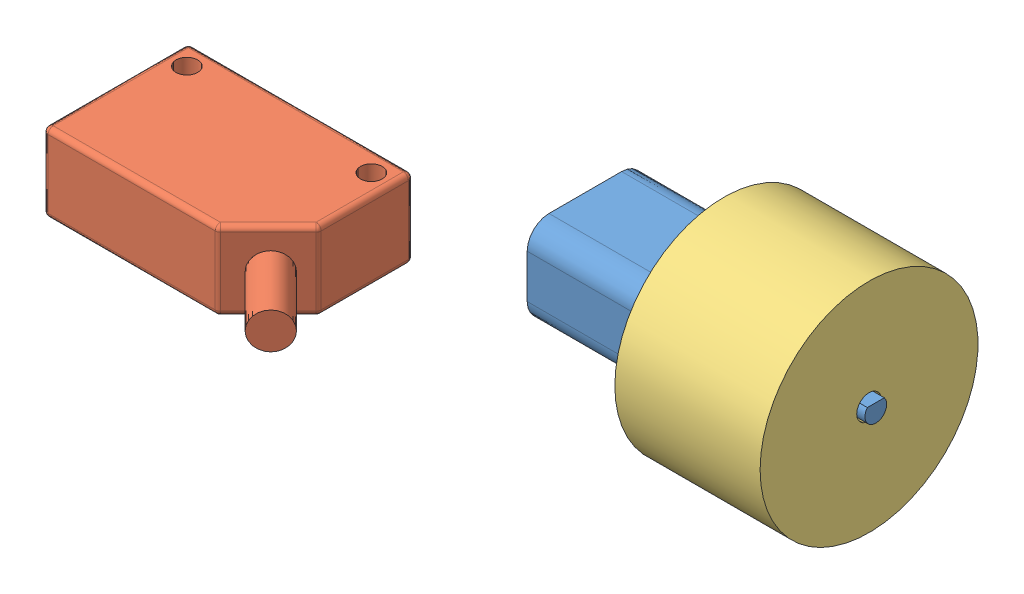
SolidWorks assembly Assem3, configuration Default. Lengths in mm.
Overall size (83.02 30 53.03).
3 component instances, 3 part files, 0 mates.
Components (placement in the parent):
- 16mm motor-1: 16mm motor [Default] at (9.2864 10.1629 34.2443) size (40 12 16)
- omron-1: omron [Default] at (-32.0327 14.8348 57.0829) size (37.72 10.8 25.16)
- tekerlek-1: tekerlek [Default] at (13.3278 16.1054 34.2165) size (20 30 30)
